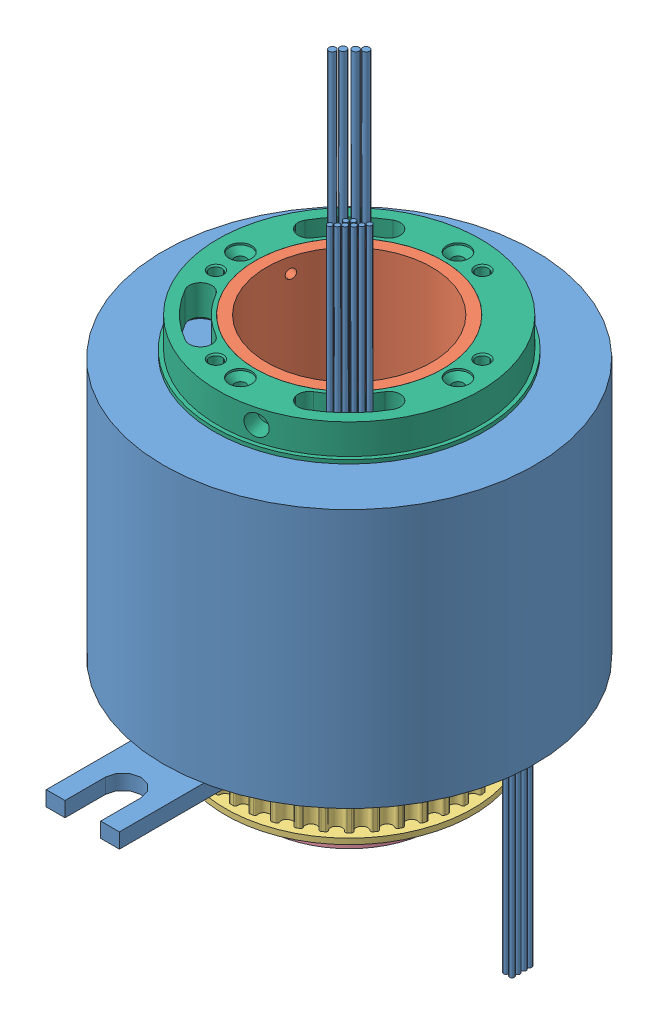
SolidWorks assembly yaw轴轴系, configuration 默认. Lengths in mm.
Overall size (101.82 170 121.91).
7 component instances, 6 part files, 16 mates.
Components (placement in the parent):
- 定制滑环H50100-12-B0265-1: 定制滑环H50100-12-B0265 [默认] at origin size (99 170 120.5)
- 大弹丸穿环铝管-1: 大弹丸穿环铝管 [默认] at (0 79 0) x (0.707107 0 0.707107) z (0 1 0) size (56.5 56.5 90.5)
- 同步带轮5M40T11mm-从动 - 副本-1: 同步带轮5M40T11mm-从动 - 副本 [GearTrax] at (0 -13 0) x (0.707107 0 -0.707107) z (0 1 0) size (66 66 14)
- 拨盘出口钢管-1: 拨盘出口钢管 [默认] at (0 -13 0) x (0.707107 0 0.707107) z (-0.707107 0 0.707107) size (46 16.5 46)
- hexagon socket head cap screws gb-3: hexagon socket head cap screws gb [GB_FASTENER_SCREWS_HSHCS M3X8-C] at (0 -18 25.75) x (0 1 0) z (0.81771 0 0.575631) size (11 5.5 5.5)
- 云台连接件-1: 云台连接件 [默认] at (0 70 0) x (0.707107 0 0.707107) z (-0.707107 0 0.707107) size (72 9 72)
- hexagon socket head cap screws gb-4: hexagon socket head cap screws gb [GB_FASTENER_SCREWS_HSHCS M3X8-C] at (23.4759 75 -23.4759) x (-0.707107 0 0.707107) z (-0.707107 0 -0.707107) size (11 5.5 5.5)
Mates (geometry in assembly coordinates):
- 同心1: concentric aligned: cylinder of 定制滑环H50100-12-B0265-1 through (0 70 0) axis (0 1 0) radius 25; cylinder of 大弹丸穿环铝管-1 through (0 79 0) axis (0 1 0) radius 25
- 重合1: coincident anti-aligned: plane of 定制滑环H50100-12-B0265-1 through (0 0 25) normal (0 -1 0); plane of 大弹丸穿环铝管-1 through (19.799 0 19.799) normal (0 1 0)
- 同心7: concentric aligned: cylinder of 大弹丸穿环铝管-1 through (0 79 0) axis (0 1 0) radius 25; cylinder of 同步带轮5M40T11mm-从动 - 副本-1 through (0 -20 0) axis (0 1 0) radius 23
- 同心8: concentric anti-aligned: cylinder of 大弹丸穿环铝管-1 through (0 -10 25.75) axis (0 -1 0) radius 1.25; cylinder of 同步带轮5M40T11mm-从动 - 副本-1 through (0 -20 25.75) axis (0 1 0) radius 1.5
- 重合22: coincident anti-aligned: plane of 大弹丸穿环铝管-1 through (16.2635 -10 16.2635) normal (0 -1 0); plane of 同步带轮5M40T11mm-从动 - 副本-1 through (0 -10 0) normal (0 1 0)
- 同心25: concentric anti-aligned: cylinder of 大弹丸穿环铝管-1 through (0 79 0) axis (0 1 0) radius 22; cylinder of 拨盘出口钢管-1 through (0 -13 0) axis (0 -1 0) radius 22
- 重合23: coincident anti-aligned: plane of 同步带轮5M40T11mm-从动 - 副本-1 through (0 -13 0) normal (0 -1 0); plane of 拨盘出口钢管-1 through (19.9758 -13 19.9758) normal (0 1 0)
- 同心26: concentric aligned: cylinder of 同步带轮5M40T11mm-从动 - 副本-1 through (0 -20 25.75) axis (0 1 0) radius 1.5; cylinder of 拨盘出口钢管-1 through (0 -28 25.75) axis (0 1 0) radius 1.5
- 同心27: concentric anti-aligned: cylinder of hexagon socket head cap screws gb-3 through (0 -7 25.75) axis (0 -1 0) radius 1.5; cylinder of 拨盘出口钢管-1 through (0 -28 25.75) axis (0 1 0) radius 1.5
- 重合24: coincident anti-aligned: plane of 拨盘出口钢管-1 through (16.2635 -15 16.2635) normal (0 -1 0); plane of hexagon socket head cap screws gb-3 through (0 -15 25.75) normal (0 1 0)
- 同心28: concentric anti-aligned: cylinder of 定制滑环H50100-12-B0265-1 through (0 70 0) axis (0 1 0) radius 25; cylinder of 云台连接件-1 through (0 79 0) axis (0 -1 0) radius 25
- 同心29: concentric anti-aligned: cylinder of 定制滑环H50100-12-B0265-1 through (-29 62 0) axis (0 1 0) radius 1.25; cylinder of 云台连接件-1 through (-29 79 0) axis (0 -1 0) radius 1.5
- 重合25: coincident anti-aligned: plane of 定制滑环H50100-12-B0265-1 through (0 70 32.5) normal (0 1 0); plane of 云台连接件-1 through (0 70 0) normal (0 -1 0)
- 同心30: concentric aligned: cylinder of 大弹丸穿环铝管-1 through (0 75 0) axis (-0.707107 0 0.707107) radius 1.25; cylinder of 云台连接件-1 through (21.3546 75 -21.3546) axis (-0.707107 0 0.707107) radius 1.5
- 同心31: concentric anti-aligned: cylinder of 云台连接件-1 through (21.3546 75 -21.3546) axis (-0.707107 0 0.707107) radius 1.5; cylinder of hexagon socket head cap screws gb-4 through (15.6978 75 -15.6978) axis (0.707107 0 -0.707107) radius 1.5
- 重合26: coincident anti-aligned: plane of 云台连接件-1 through (21.3546 75 -21.3546) normal (0.707107 0 -0.707107); plane of hexagon socket head cap screws gb-4 through (21.3546 75 -21.3546) normal (-0.707107 0 0.707107)
